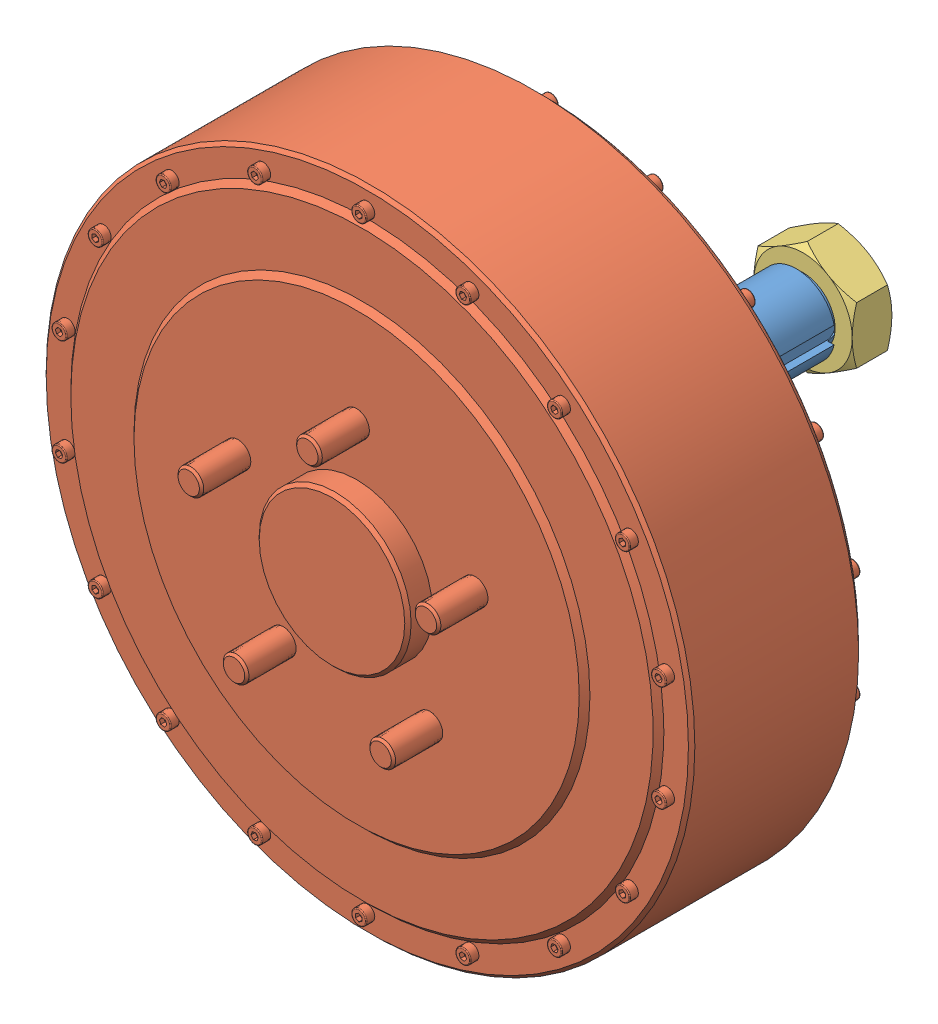
SolidWorks assembly Motor_QSWP96V8000W, configuration -0. Lengths in mm.
Overall size (303 303 250).
3 component instances, 3 part files, 2 mates.
Components (placement in the parent):
- Motor_QSWP96V8000W-Part-1-1: Motor_QSWP96V8000W-Part-1 [Výchozí] at origin size (40 40 82.5)
- Motor_QSWP96V8000W-Part-2-1: Motor_QSWP96V8000W-Part-2 [Výchozí] at origin size (303 303 166)
- Motor_QSWP96V8000W-Part-3-1: Motor_QSWP96V8000W-Part-3 [Výchozí] at (0 0 -2) size (46 53.12 18.5)
Mates (geometry in assembly coordinates):
- Vzdálenost1: distance = 62 mm: plane of Motor_QSWP96V8000W-Part-1-1 through (-20 0 -158) normal (0 0 -1); plane of Motor_QSWP96V8000W-Part-3-1 through (0 26.5581 -220) normal (0 0 1)
- Soustředná1: concentric aligned: cylinder of Motor_QSWP96V8000W-Part-1-1 through (0 0 21.9632) axis (0 0 1) radius 15; cylinder of Motor_QSWP96V8000W-Part-3-1 through (0 0 -238.5) axis (0 0 1) radius 14
